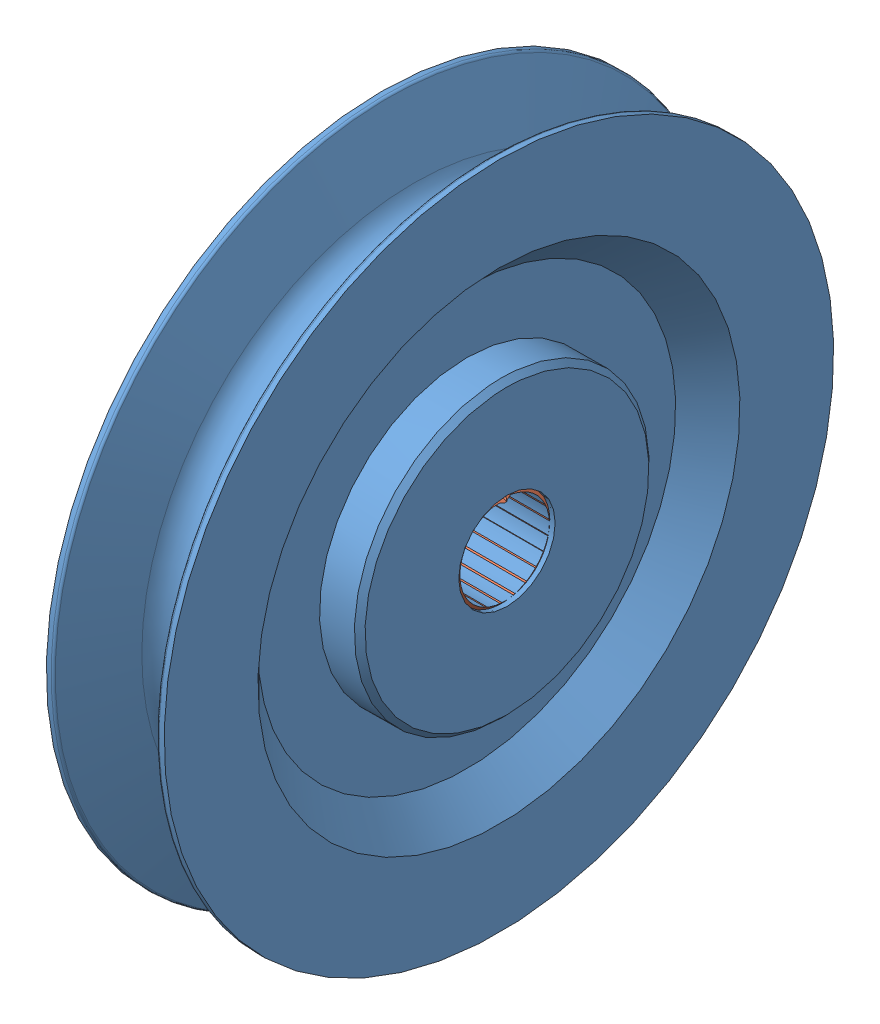
SolidWorks assembly 1-401-04-Seilrolle-125-Buchse-komplett.stp, configuration Default. Lengths in mm.
Overall size (25.1 125 125).
2 component instances, 2 part files, 0 mates.
Components (placement in the parent):
- F8125 Buchse.stp-1: F8125 Buchse.stp [Default] at origin size (25 125 125)
- Lagerbuchse 1625-DU.stp-1: Lagerbuchse 1625-DU.stp [Default] at (-12.5 0 0) x (0 0 -1) z (1 0 0) size (18 17.98 25.1)
